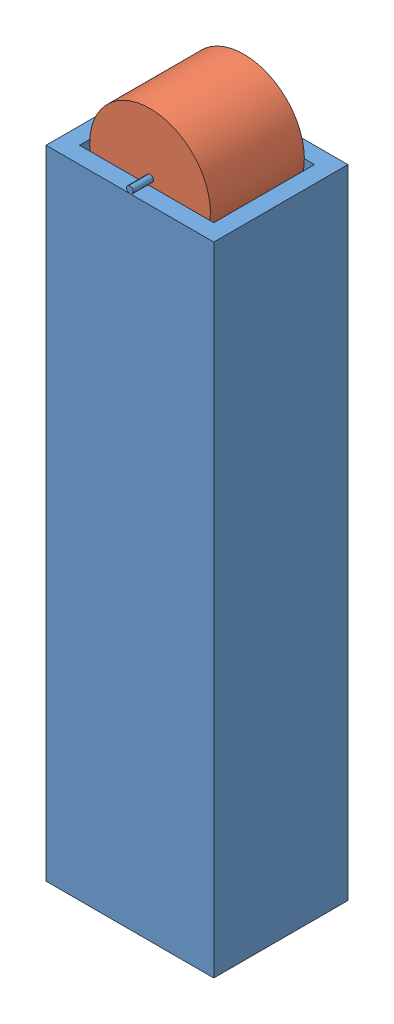
SolidWorks assembly rack_base_assembly, configuration Default. Lengths in mm.
Overall size (25.21 108.1 20.03).
2 component instances, 2 part files, 2 mates.
Components (placement in the parent):
- rack_base-1: rack_base [Default] at (48.9053 23.8478 71.4314) size (25 96 20.03)
- rack_support-1: rack_support [Default] at (-16.9016 78.81 71.4314) x (-0.79794 -0.602737 0) z (0 0 1) size (18 18 14)
Mates (geometry in assembly coordinates):
- Concentric1: concentric aligned: cylinder of rack_base-1 through (10.9842 74.1578 61.4314) axis (0 0 1) radius 0.5; cylinder of rack_support-1 through (10.9842 74.1578 64.4314) axis (0 0 1) radius 0.5
- Distance1: distance = 0.5 mm: plane of rack_support-1 through (10.9842 74.1578 78.4314) normal (0 0 1); line of rack_base-1 through (10.941 73.6597 78.9314) axis (-1 0 0)
